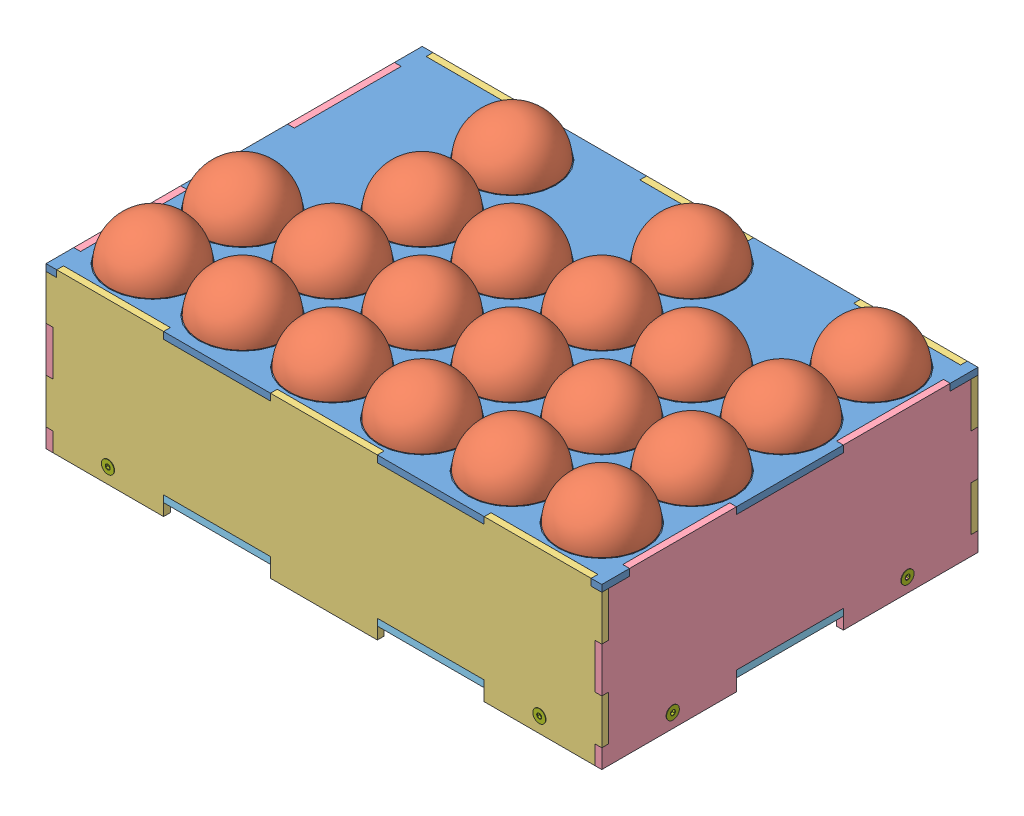
SolidWorks assembly Face Plate Assembly, configuration Default. Lengths in mm.
Overall size (266.16 95 182.16).
62 component instances, 8 part files, 20 mates.
Components (placement in the parent):
- Face Plate-1: Face Plate [Default] at origin size (260 3.17 176)
- Diffuser-1: Diffuser [Default] at (105 1.5875 63) x (0.786506 0 -0.617583) z (0.617583 0 0.786506) size (40 20 40)
- Diffuser-2: Diffuser [Default] at (63 1.5875 63) x (0.786506 0 -0.617583) z (0.617583 0 0.786506) size (40 20 40)
- Diffuser-3: Diffuser [Default] at (21 1.5875 63) x (0.786506 0 -0.617583) z (0.617583 0 0.786506) size (40 20 40)
- Diffuser-4: Diffuser [Default] at (-21 1.5875 63) x (0.786506 0 -0.617583) z (0.617583 0 0.786506) size (40 20 40)
- Diffuser-5: Diffuser [Default] at (-63 1.5875 63) x (0.786506 0 -0.617583) z (0.617583 0 0.786506) size (40 20 40)
- Diffuser-6: Diffuser [Default] at (-105 1.5875 63) x (0.786506 0 -0.617583) z (0.617583 0 0.786506) size (40 20 40)
- Diffuser-7: Diffuser [Default] at (105 1.5875 21) x (0.786506 0 -0.617583) z (0.617583 0 0.786506) size (40 20 40)
- Diffuser-8: Diffuser [Default] at (63 1.5875 21) x (0.786506 0 -0.617583) z (0.617583 0 0.786506) size (40 20 40)
- Diffuser-9: Diffuser [Default] at (21 1.5875 21) x (0.786506 0 -0.617583) z (0.617583 0 0.786506) size (40 20 40)
- Diffuser-10: Diffuser [Default] at (-21 1.5875 21) x (0.786506 0 -0.617583) z (0.617583 0 0.786506) size (40 20 40)
- Diffuser-11: Diffuser [Default] at (-63 1.5875 21) x (0.786506 0 -0.617583) z (0.617583 0 0.786506) size (40 20 40)
- Diffuser-12: Diffuser [Default] at (-105 1.5875 21) x (0.786506 0 -0.617583) z (0.617583 0 0.786506) size (40 20 40)
- Diffuser-13: Diffuser [Default] at (105 1.5875 -21) x (0.786506 0 -0.617583) z (0.617583 0 0.786506) size (40 20 40)
- Diffuser-14: Diffuser [Default] at (63 1.5875 -21) x (0.786506 0 -0.617583) z (0.617583 0 0.786506) size (40 20 40)
- Diffuser-15: Diffuser [Default] at (21 1.5875 -21) x (0.786506 0 -0.617583) z (0.617583 0 0.786506) size (40 20 40)
- Diffuser-16: Diffuser [Default] at (-21 1.5875 -21) x (0.786506 0 -0.617583) z (0.617583 0 0.786506) size (40 20 40)
- Diffuser-17: Diffuser [Default] at (-63 1.5875 -21) x (0.786506 0 -0.617583) z (0.617583 0 0.786506) size (40 20 40)
- Diffuser-18: Diffuser [Default] at (105 1.5875 -63) x (0.786506 0 -0.617583) z (0.617583 0 0.786506) size (40 20 40)
- Diffuser-19: Diffuser [Default] at (21 1.5875 -63) x (0.786506 0 -0.617583) z (0.617583 0 0.786506) size (40 20 40)
- Diffuser-20: Diffuser [Default] at (-63 1.5875 -63) x (0.786506 0 -0.617583) z (0.617583 0 0.786506) size (40 20 40)
- Bottom Plate-1: Bottom Plate [Default] at (-130 -73.4125 -88) size (260 75 3.17)
- Bottom Plate-2: Bottom Plate [Default] at (-130 -73.4125 84.825) size (260 75 3.17)
- Side Plate-2: Side Plate [Default] at (128.4125 -73.4125 88) x (0 0 -1) z (1 0 0) size (176 75 3.17)
- Side Plate-3: Side Plate [Default] at (-128.4125 -73.4125 88) x (0 0 -1) z (1 0 0) size (176 75 3.17)
- Back Plate-1: Back Plate [Default] at (-130 -66.175 88) size (260 3.17 176)
- 90592A085_STEEL HEX NUT-1: 90592A085_STEEL HEX NUT [90592A085] at (100.9125 -66.175 80.375) x (0.96375 0.266809 0) z (0 0 1) size (5.5 6.35 2.78)
- 91294A133_BLACK ALLOY STEEL FLAT-HEAD SOCKET CAP SCREW-1: 91294A133_BLACK ALLOY STEEL FLAT-HEAD SOCKET CAP SCREW [91294A133] at (100.9125 -66.175 88.2) x (-0.99907 -0.043126 0) z (0 0 1) size (6 6 14.33)
- 91294A133_BLACK ALLOY STEEL FLAT-HEAD SOCKET CAP SCREW-3: 91294A133_BLACK ALLOY STEEL FLAT-HEAD SOCKET CAP SCREW [91294A133] at (130.2 -66.7938 54.9125) x (0 0.80636 -0.591426) z (1 0 0) size (6 6 14.33)
- 90592A085_STEEL HEX NUT-3: 90592A085_STEEL HEX NUT [90592A085] at (122.375 -66.7938 54.9125) x (0 0.999348 -0.036096) z (1 0 0) size (5.5 6.35 2.78)
- 91294A133_BLACK ALLOY STEEL FLAT-HEAD SOCKET CAP SCREW-4: 91294A133_BLACK ALLOY STEEL FLAT-HEAD SOCKET CAP SCREW [91294A133] at (100.9125 -66.175 -88.2) x (-0.99907 -0.043126 0) z (0 0 -1) size (6 6 14.33)
- 90592A085_STEEL HEX NUT-4: 90592A085_STEEL HEX NUT [90592A085] at (122.375 -66.7938 -54.9125) x (0 0.999348 0.036096) z (1 0 0) size (5.5 6.35 2.78)
- 91294A133_BLACK ALLOY STEEL FLAT-HEAD SOCKET CAP SCREW-5: 91294A133_BLACK ALLOY STEEL FLAT-HEAD SOCKET CAP SCREW [91294A133] at (130.2 -66.7938 -54.9125) x (0 -0.80636 -0.591426) z (1 0 0) size (6 6 14.33)
- 90592A085_STEEL HEX NUT-5: 90592A085_STEEL HEX NUT [90592A085] at (100.9125 -66.175 -80.3575) x (0.96375 0.266809 0) z (0 0 1) size (5.5 6.35 2.78)
- 91294A133_BLACK ALLOY STEEL FLAT-HEAD SOCKET CAP SCREW-6: 91294A133_BLACK ALLOY STEEL FLAT-HEAD SOCKET CAP SCREW [91294A133] at (-100.9125 -66.175 88.2) x (0.99907 -0.043126 0) z (0 0 1) size (6 6 14.33)
- 90592A085_STEEL HEX NUT-6: 90592A085_STEEL HEX NUT [90592A085] at (-122.375 -66.7938 54.9125) x (0 0.999348 -0.036096) z (-1 0 0) size (5.5 6.35 2.78)
- 91294A133_BLACK ALLOY STEEL FLAT-HEAD SOCKET CAP SCREW-7: 91294A133_BLACK ALLOY STEEL FLAT-HEAD SOCKET CAP SCREW [91294A133] at (-130.2 -66.7938 54.9125) x (0 -0.80636 0.591426) z (-1 0 0) size (6 6 14.33)
- 90592A085_STEEL HEX NUT-7: 90592A085_STEEL HEX NUT [90592A085] at (-100.9125 -66.175 80.3575) x (-0.96375 0.266809 0) z (0 0 -1) size (5.5 6.35 2.78)
- 91294A133_BLACK ALLOY STEEL FLAT-HEAD SOCKET CAP SCREW-8: 91294A133_BLACK ALLOY STEEL FLAT-HEAD SOCKET CAP SCREW [91294A133] at (-100.9125 -66.175 -88.2) x (0.99907 -0.043126 0) z (0 0 -1) size (6 6 14.33)
- 90592A085_STEEL HEX NUT-8: 90592A085_STEEL HEX NUT [90592A085] at (-122.375 -66.7938 -54.9125) x (0 0.999348 0.036096) z (-1 0 0) size (5.5 6.35 2.78)
- 91294A133_BLACK ALLOY STEEL FLAT-HEAD SOCKET CAP SCREW-9: 91294A133_BLACK ALLOY STEEL FLAT-HEAD SOCKET CAP SCREW [91294A133] at (-130.2 -66.7938 -54.9125) x (0 0.80636 0.591426) z (-1 0 0) size (6 6 14.33)
- 90592A085_STEEL HEX NUT-9: 90592A085_STEEL HEX NUT [90592A085] at (-100.9125 -66.175 -80.375) x (-0.96375 0.266809 0) z (0 0 -1) size (5.5 6.35 2.78)
- LED 5mm-1: LED 5mm [Default] at (105 1.5875 63.25) x (1 0 0) z (0 1 0) size (5.5 6 17.5)
- LED 5mm-2: LED 5mm [Default] at (105 1.5875 21.25) x (1 0 0) z (0 1 0) size (5.5 6 17.5)
- LED 5mm-3: LED 5mm [Default] at (105 1.5875 -20.75) x (1 0 0) z (0 1 0) size (5.5 6 17.5)
- LED 5mm-4: LED 5mm [Default] at (105 1.5875 -62.75) x (1 0 0) z (0 1 0) size (5.5 6 17.5)
- LED 5mm-5: LED 5mm [Default] at (63 1.5875 63.25) x (1 0 0) z (0 1 0) size (5.5 6 17.5)
- LED 5mm-6: LED 5mm [Default] at (63 1.5875 21.25) x (1 0 0) z (0 1 0) size (5.5 6 17.5)
- LED 5mm-7: LED 5mm [Default] at (63 1.5875 -20.75) x (1 0 0) z (0 1 0) size (5.5 6 17.5)
- LED 5mm-8: LED 5mm [Default] at (21 1.5875 63.25) x (1 0 0) z (0 1 0) size (5.5 6 17.5)
- LED 5mm-9: LED 5mm [Default] at (21 1.5875 21.25) x (1 0 0) z (0 1 0) size (5.5 6 17.5)
- LED 5mm-10: LED 5mm [Default] at (21 1.5875 -20.75) x (1 0 0) z (0 1 0) size (5.5 6 17.5)
- LED 5mm-11: LED 5mm [Default] at (21 1.5875 -62.75) x (1 0 0) z (0 1 0) size (5.5 6 17.5)
- LED 5mm-12: LED 5mm [Default] at (-21 1.5875 63.25) x (1 0 0) z (0 1 0) size (5.5 6 17.5)
- LED 5mm-13: LED 5mm [Default] at (-21 1.5875 21.25) x (1 0 0) z (0 1 0) size (5.5 6 17.5)
- LED 5mm-14: LED 5mm [Default] at (-21 1.5875 -20.75) x (1 0 0) z (0 1 0) size (5.5 6 17.5)
- LED 5mm-15: LED 5mm [Default] at (-63 1.5875 63.25) x (1 0 0) z (0 1 0) size (5.5 6 17.5)
- LED 5mm-16: LED 5mm [Default] at (-63 1.5875 21.25) x (1 0 0) z (0 1 0) size (5.5 6 17.5)
- LED 5mm-17: LED 5mm [Default] at (-63 1.5875 -20.75) x (1 0 0) z (0 1 0) size (5.5 6 17.5)
- LED 5mm-18: LED 5mm [Default] at (-63 1.5875 -62.75) x (1 0 0) z (0 1 0) size (5.5 6 17.5)
- LED 5mm-19: LED 5mm [Default] at (-105 1.5875 63.25) x (1 0 0) z (0 1 0) size (5.5 6 17.5)
- LED 5mm-20: LED 5mm [Default] at (-105 1.5875 21.25) x (1 0 0) z (0 1 0) size (5.5 6 17.5)
Mates (geometry in assembly coordinates):
- Concentric1: concentric aligned: circle of Face Plate-1; circle of Diffuser-1
- Tangent2: tangent: circle of Face Plate-1; plane of Diffuser-1 through (105 1.5875 63) normal (0 -1 0)
- Coincident5: coincident anti-aligned: plane of Face Plate-1 through (75 1.5875 0) normal (1 0 0); plane of Bottom Plate-1 through (75 -73.4125 -84.825) normal (-1 0 0)
- Coincident7: coincident anti-aligned: line of Face Plate-1 through (75 -1.5875 -88) axis (-1 0 0); line of Bottom Plate-1 through (25 -1.5875 -88) axis (1 0 0)
- Coincident8: coincident anti-aligned: line of Face Plate-1 through (126.825 1.5875 75) axis (0 0 -1); line of Side Plate-2 through (126.825 1.5875 25) axis (0 0 1)
- Coincident10: coincident anti-aligned: plane of Bottom Plate-1 through (-130 -64.5875 -84.825) normal (0 -1 0); plane of Back Plate-1 through (-130 -64.5875 88) normal (0 1 0)
- Coincident11: coincident anti-aligned: plane of Side Plate-2 through (130 -73.4125 25) normal (0 0 -1); plane of Back Plate-1 through (-130 -64.5875 25) normal (0 0 1)
- Coincident12: coincident anti-aligned: line of Side Plate-2 through (130 -64.5875 -25) axis (0 0 1); line of Back Plate-1 through (130 -64.5875 25) axis (0 0 -1)
- Concentric2: concentric anti-aligned: cylinder of Bottom Plate-2 through (100.9125 -66.175 88) axis (0 0 -1) radius 1.575; cylinder of 91294A133_BLACK ALLOY STEEL FLAT-HEAD SOCKET CAP SCREW-1 through (100.9125 -66.175 88.2) axis (0 0 1) radius 3
- Coincident15: coincident aligned: line of Bottom Plate-1 through (130 -43.5875 -88) axis (0 -1 0); line of Side Plate-2 through (130 -22.5875 -88) axis (0 -1 0)
- Coincident16: coincident aligned: plane of Bottom Plate-2 through (-130 -73.4125 88) normal (0 0 1); circle of 91294A133_BLACK ALLOY STEEL FLAT-HEAD SOCKET CAP SCREW-1
- Distance2: distance = 0.35 mm anti-aligned: plane of Back Plate-1 through (-130 -67.7625 78.825) normal (0 0 1); plane of 90592A085_STEEL HEX NUT-1 through (97.8386 -65.3786 79.175) normal (0 0 -1)
- Concentric4: concentric anti-aligned: circle of Bottom Plate-2; circle of 90592A085_STEEL HEX NUT-1
- Concentric5: concentric anti-aligned: cylinder of Side Plate-2 through (130 -66.7938 54.9125) axis (-1 0 0) radius 1.575; circle of 91294A133_BLACK ALLOY STEEL FLAT-HEAD SOCKET CAP SCREW-3
- Coincident21: coincident aligned: plane of Side Plate-2 through (130 -73.4125 88) normal (1 0 0); circle of 91294A133_BLACK ALLOY STEEL FLAT-HEAD SOCKET CAP SCREW-3
- Concentric8: concentric aligned: circle of 91294A133_BLACK ALLOY STEEL FLAT-HEAD SOCKET CAP SCREW-3; circle of 90592A085_STEEL HEX NUT-3
- Distance1: distance = 0.35 mm anti-aligned: plane of 90592A085_STEEL HEX NUT-3 through (121.175 -69.4846 56.5984) normal (-1 0 0); plane of Back Plate-1 through (120.825 -67.7625 88) normal (1 0 0)
- Coincident28: coincident anti-aligned: plane of Face Plate-1 through (104.23 13.0875 0) normal (-1 0 0); plane of LED 5mm-1 through (104.23 1.5875 63) normal (1 0 0)
- Coincident29: coincident anti-aligned: plane of Face Plate-1 through (0 13.0875 63.5) normal (0 0 -1); plane of LED 5mm-1 through (105 1.5875 63.5) normal (0 0 1)
- Coincident30: coincident anti-aligned: plane of Face Plate-1 through (0 1.5875 0) normal (0 1 0); plane of LED 5mm-1 through (105 1.5875 63.25) normal (0 -1 0)
